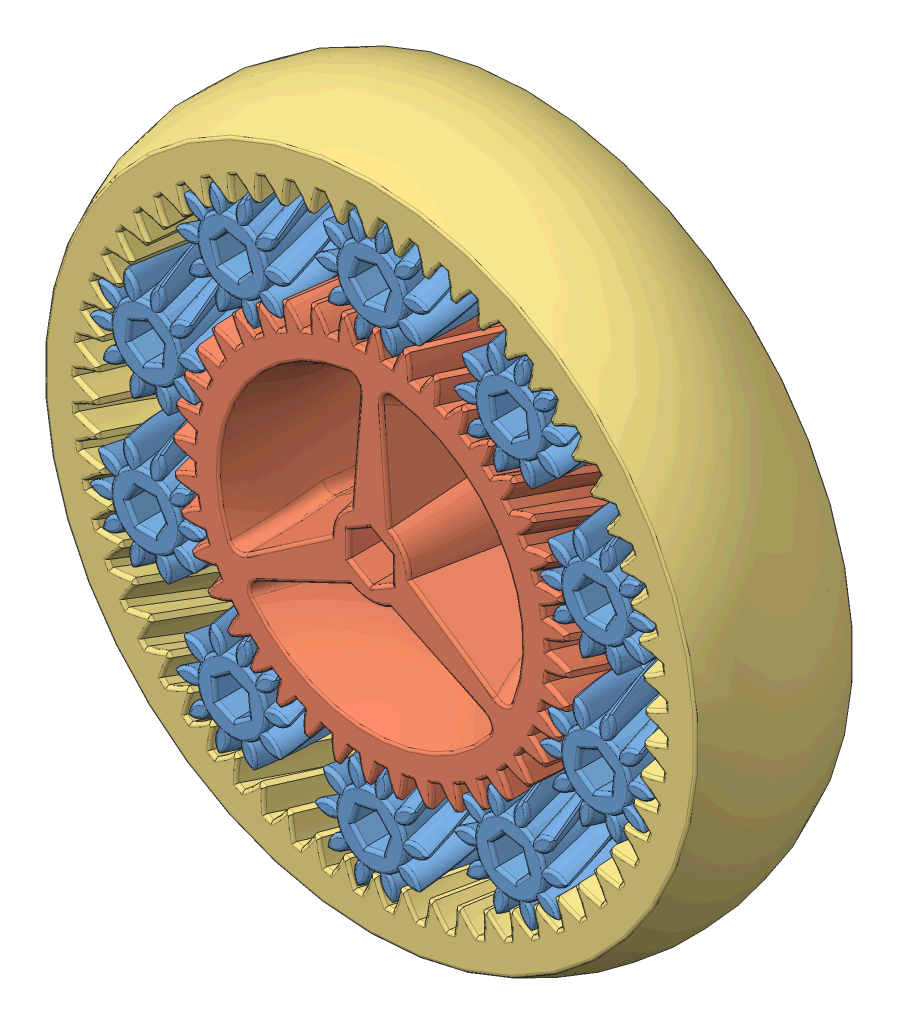
SolidWorks assembly Planetary 04, configuration Default. Lengths in mm.
Overall size (66.02 66.02 23.37).
12 component instances, 3 part files, 8 mates.
Components (placement in the parent):
- Planet-Gear-04-2: Planet-Gear-04 [ISO - Spur gear 0.9M 10T 20PA 7.5FW ---S10A75H50L1.0N] at (0 22.5 0) x (0 0 -1) z (0.951057 -0.309017 0) size (15.08 10.83 10.85)
- Sun-Gear-04-2: Sun-Gear-04 [ISO - Spur gear 0.9M 40T 20PA 7.5FW ---S40A75H50L30.0N] x (0 0 1) z (-1 0 0) size (15.05 37.86 37.86)
- Ring-Gear-04-1: Ring-Gear-04 [ISO - Internal spur gear 0.9M 60T 20PA 7.5FW ---S60S60OD 1.0AF] x (0 0 -1) z (1 0 0) size (23.35 66.02 66.02)
- Planet-Gear-04-3: Planet-Gear-04 [ISO - Spur gear 0.9M 10T 20PA 7.5FW ---S10A75H50L1.0N] at (-13.2252 18.2029 0) x (0 0 -1) z (0.951057 0.309017 0) size (15.08 10.83 10.85)
- Planet-Gear-04-4: Planet-Gear-04 [ISO - Spur gear 0.9M 10T 20PA 7.5FW ---S10A75H50L1.0N] at (-21.3988 6.9529 0) x (0 0 -1) z (0.587785 0.809017 0) size (15.08 10.83 10.85)
- Planet-Gear-04-5: Planet-Gear-04 [ISO - Spur gear 0.9M 10T 20PA 7.5FW ---S10A75H50L1.0N] at (-21.3988 -6.9529 0) x (0 0 -1) z (0 1 0) size (15.08 10.83 10.85)
- Planet-Gear-04-6: Planet-Gear-04 [ISO - Spur gear 0.9M 10T 20PA 7.5FW ---S10A75H50L1.0N] at (-13.2252 -18.2029 0) x (0 0 -1) z (-0.587785 0.809017 0) size (15.08 10.83 10.85)
- Planet-Gear-04-7: Planet-Gear-04 [ISO - Spur gear 0.9M 10T 20PA 7.5FW ---S10A75H50L1.0N] at (0 -22.5 0) x (0 0 -1) z (-0.951057 0.309017 0) size (15.08 10.83 10.85)
- Planet-Gear-04-8: Planet-Gear-04 [ISO - Spur gear 0.9M 10T 20PA 7.5FW ---S10A75H50L1.0N] at (13.2252 -18.2029 0) x (0 0 -1) z (-0.951057 -0.309017 0) size (15.08 10.83 10.85)
- Planet-Gear-04-9: Planet-Gear-04 [ISO - Spur gear 0.9M 10T 20PA 7.5FW ---S10A75H50L1.0N] at (21.3988 -6.9529 0) x (0 0 -1) z (-0.587785 -0.809017 0) size (15.08 10.83 10.85)
- Planet-Gear-04-10: Planet-Gear-04 [ISO - Spur gear 0.9M 10T 20PA 7.5FW ---S10A75H50L1.0N] at (21.3988 6.9529 0) x (0 0 -1) z (0 -1 0) size (15.08 10.83 10.85)
- Planet-Gear-04-11: Planet-Gear-04 [ISO - Spur gear 0.9M 10T 20PA 7.5FW ---S10A75H50L1.0N] at (13.2252 18.2029 0) x (0 0 -1) z (0.587785 -0.809017 0) size (15.08 10.83 10.85)
Mates (geometry in assembly coordinates):
- Coincident3: coincident: plane of Planet-Gear-04-2 through (0 22.5 0) normal (0 0 -1); plane of assembly through (0 0 0) normal (0 0 1)
- Concentric1: concentric: circle of Planet-Gear-04-2; circle of assembly
- Coincident4: coincident: plane of Sun-Gear-04-2 through (0 0 0) normal (0 0 1); plane of assembly through (0 0 0) normal (0 0 1)
- Concentric2: concentric: circle of Sun-Gear-04-2; circle of assembly
- Angle2: planar angle = 0.314159 rad: plane of Planet-Gear-04-2 through (0 22.5 0) normal (0.951057 -0.309017 0); plane of assembly through (0 0 0) normal (1 0 0)
- Coincident7: coincident: plane of Sun-Gear-04-2 through (0 0 0) normal (-1 0 0); plane of assembly through (0 0 0) normal (1 0 0)
- Coincident8: coincident: plane of Ring-Gear-04-1 through (0 0 0) normal (0 0 -1); plane of assembly through (0 0 0) normal (0 0 1)
- Concentric3: concentric: circle of Ring-Gear-04-1; circle of assembly
